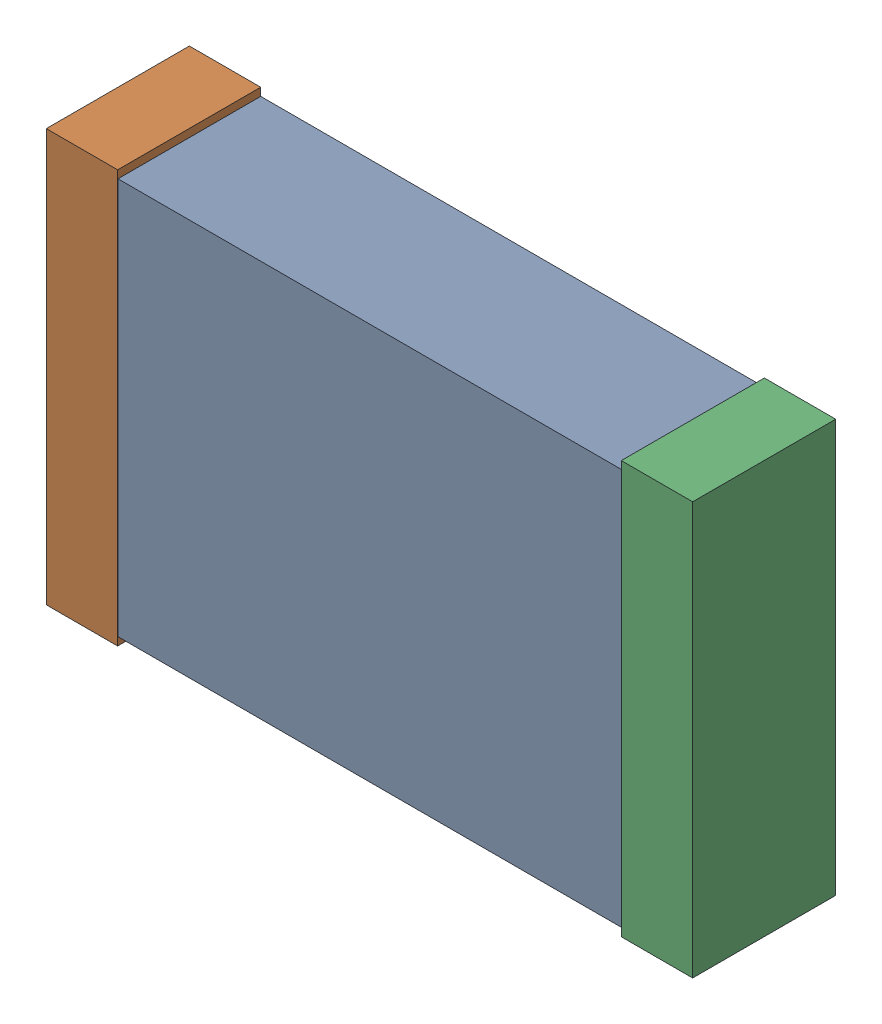
SolidWorks assembly C1, configuration Default. Lengths in mm.
Overall size (2.04 1.3 0.45).
6 component instances, 2 part files, 0 mates.
Components (placement in the parent):
- 870943200-1: 870943200 [Default] at (73.3544 7.1606 0) size (2 1.25 0.45)
  - Extruded_39-1: Extruded_39 [Default] at origin size (2 1.25 0.45)
- 870943360-1: 870943360 [Default] at (72.4419 7.1606 0) size (0.23 1.3 0.45)
  - Extruded_40-1: Extruded_40 [Default] at origin size (0.23 1.3 0.45)
- 870943360-2: 870943360 [Default] at (74.2544 7.1606 0) size (0.23 1.3 0.45)
  - Extruded_40-1: Extruded_40 [Default] at origin size (0.23 1.3 0.45)
